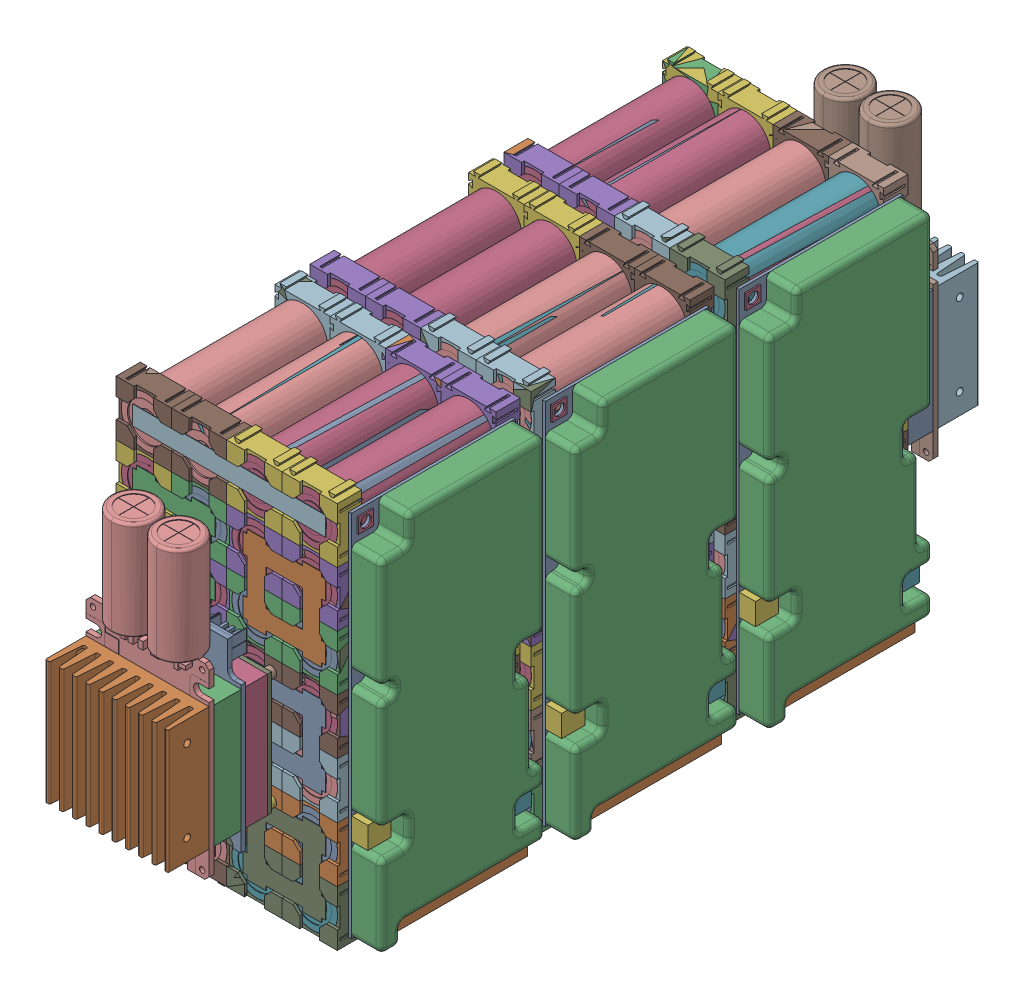
SolidWorks assembly ElectricAssy, configuration Standard. Lengths in mm.
Overall size (94.27 144.35 296.99).
3 component instances, 2 part files, 0 mates.
Components (placement in the parent):
- Battery-1: Battery [Standard] at (-10.6269 -2.705 0) size (94.27 144.35 209)
- Controller_HBCi10063-3: Controller_HBCi10063 [Standard] at (-47.1678 -49.3154 47.3381) size (45 104.5 39.9)
- Controller_HBCi10063-4: Controller_HBCi10063 [Standard] at (11.9485 -49.3154 -48.0273) x (-1 0 0) z (0 0 -1) size (45 104.5 39.9)
